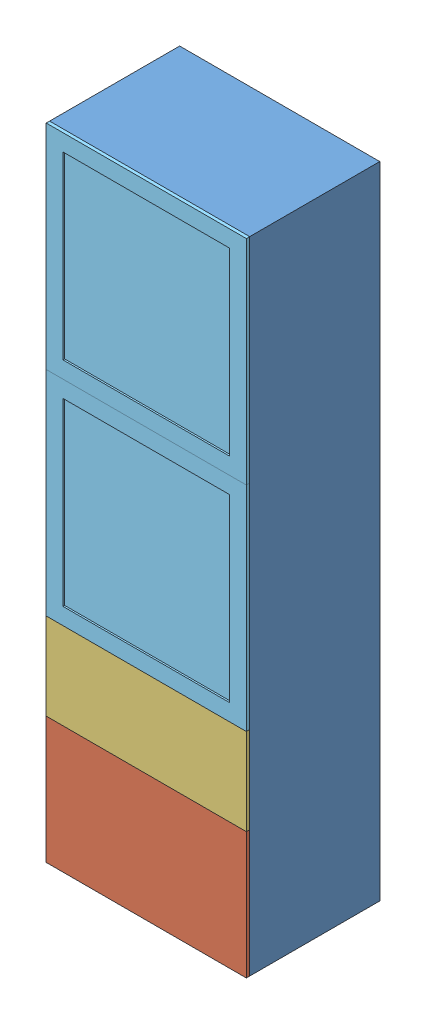
SolidWorks assembly Schrank-L, configuration Standard. Lengths in mm.
Overall size (600 1920 400).
10 component instances, 5 part files, 23 mates.
Components (placement in the parent):
- Schrank-Korpus-1: Schrank-Korpus [Standard] at (-405.9631 38.7369 1725) size (600 1920 390)
- Schublade-Hoch-1: Schublade-Hoch [Standard] at (-405.9631 -731.2631 2115) size (600 380 380)
- Schublade-Tief-1: Schublade-Tief [Standard] at (-405.9631 -411.2631 2115) size (600 260 380)
- Regalbrett-1: Regalbrett [Standard] at (-405.9631 -286.2631 1735) x (1 0 0) z (0 -1 0) size (560 360 10)
- Regalbrett-2: Regalbrett [Standard] at (-405.9631 -20.5713 1735) x (1 0 0) z (0 -1 0) size (560 360 10)
- Regalbrett-3: Regalbrett [Standard] at (-405.9631 223.3159 1735) x (1 0 0) z (0 -1 0) size (560 360 10)
- Regalbrett-4: Regalbrett [Standard] at (-405.9631 479.3348 1735) x (1 0 0) z (0 -1 0) size (560 360 10)
- Regalbrett-5: Regalbrett [Standard] at (-405.9631 753.23 1735) x (1 0 0) z (0 -1 0) size (560 360 10)
- SINDVIK-Vitrinentüre-1: SINDVIK-Vitrinentüre [Standard] at (-405.9631 38.7369 2115) size (600 640 10)
- SINDVIK-Vitrinentüre-2: SINDVIK-Vitrinentüre [Standard] at (-405.9631 678.7369 2115) size (600 640 10)
Mates (geometry in assembly coordinates):
- Deckungsgleich1: coincident anti-aligned: plane of Schrank-Korpus-1 through (-125.9631 978.7369 2115) normal (-1 0 0); plane of Schublade-Hoch-1 through (-125.9631 -901.2631 1755) normal (1 0 0)
- Deckungsgleich2: coincident anti-aligned: plane of Schrank-Korpus-1 through (-125.9631 978.7369 2115) normal (-1 0 0); plane of Schublade-Tief-1 through (-125.9631 -321.2631 1755) normal (1 0 0)
- Deckungsgleich3: coincident anti-aligned: plane of Schrank-Korpus-1 through (-405.9631 38.7369 1735) normal (0 0 1); plane of Regalbrett-1 through (-405.9631 -286.2631 1735) normal (0 0 -1)
- Deckungsgleich4: coincident aligned: plane of Schublade-Tief-1 through (-705.9631 -281.2631 2125) normal (0 1 0); plane of Regalbrett-1 through (-685.9631 -281.2631 2095) normal (0 1 0)
- Deckungsgleich5: coincident: plane of Schrank-Korpus-1 through (-405.9631 38.7369 1735) normal (0 0 1); plane of Regalbrett-2 through (-405.9631 -20.5713 1735) normal (0 0 -1)
- Deckungsgleich6: coincident: plane of Schrank-Korpus-1 through (-405.9631 38.7369 1735) normal (0 0 1); plane of Regalbrett-3 through (-405.9631 223.3159 1735) normal (0 0 -1)
- Deckungsgleich7: coincident: plane of Schrank-Korpus-1 through (-405.9631 38.7369 1735) normal (0 0 1); plane of Regalbrett-4 through (-405.9631 479.3348 1735) normal (0 0 -1)
- Deckungsgleich8: coincident: plane of Schrank-Korpus-1 through (-405.9631 38.7369 1735) normal (0 0 1); plane of Regalbrett-5 through (-405.9631 753.23 1735) normal (0 0 -1)
- Deckungsgleich9: coincident anti-aligned: plane of Schrank-Korpus-1 through (-685.9631 978.7369 2115) normal (1 0 0); plane of Regalbrett-5 through (-685.9631 748.23 2095) normal (-1 0 0)
- Deckungsgleich10: coincident anti-aligned: plane of Schrank-Korpus-1 through (-685.9631 978.7369 2115) normal (1 0 0); plane of Regalbrett-4 through (-685.9631 474.3348 2095) normal (-1 0 0)
- Deckungsgleich11: coincident anti-aligned: plane of Schrank-Korpus-1 through (-685.9631 978.7369 2115) normal (1 0 0); plane of Regalbrett-3 through (-685.9631 218.3159 2095) normal (-1 0 0)
- Deckungsgleich12: coincident anti-aligned: plane of Schrank-Korpus-1 through (-685.9631 978.7369 2115) normal (1 0 0); plane of Regalbrett-2 through (-685.9631 -25.5713 2095) normal (-1 0 0)
- Deckungsgleich13: coincident anti-aligned: plane of Schrank-Korpus-1 through (-685.9631 978.7369 2115) normal (1 0 0); plane of Regalbrett-1 through (-685.9631 -291.2631 2095) normal (-1 0 0)
- Deckungsgleich14: coincident anti-aligned: plane of Schrank-Korpus-1 through (-685.9631 -901.2631 2115) normal (0 1 0); plane of Schublade-Hoch-1 through (-685.9631 -901.2631 1755) normal (0 -1 0)
- Deckungsgleich15: coincident: line of Schublade-Hoch-1 through (-105.9631 -541.2631 2115) axis (-1 0 0); plane of Schublade-Tief-1 through (-705.9631 -541.2631 2125) normal (0 -1 0)
- Deckungsgleich16: coincident anti-aligned: plane of Schrank-Korpus-1 through (-405.9631 38.7369 2115) normal (0 0 1); plane of Schublade-Hoch-1 through (-405.9631 -731.2631 2115) normal (0 0 -1)
- Deckungsgleich17: coincident anti-aligned: plane of Schrank-Korpus-1 through (-405.9631 38.7369 2115) normal (0 0 1); plane of Schublade-Tief-1 through (-405.9631 -411.2631 2115) normal (0 0 -1)
- Deckungsgleich18: coincident anti-aligned: plane of Schrank-Korpus-1 through (-405.9631 38.7369 2115) normal (0 0 1); plane of SINDVIK-Vitrinentüre-1 through (-405.9631 38.7369 2115) normal (0 0 -1)
- Deckungsgleich19: coincident: plane of Schrank-Korpus-1 through (-405.9631 38.7369 2115) normal (0 0 1); plane of SINDVIK-Vitrinentüre-2 through (-405.9631 678.7369 2115) normal (0 0 -1)
- Deckungsgleich20: coincident anti-aligned: plane of Schublade-Tief-1 through (-705.9631 -281.2631 2125) normal (0 1 0); plane of SINDVIK-Vitrinentüre-1 through (-705.9631 -281.2631 2125) normal (0 -1 0)
- Deckungsgleich21: coincident: plane of SINDVIK-Vitrinentüre-1 through (-705.9631 358.7369 2125) normal (0 1 0); plane of SINDVIK-Vitrinentüre-2 through (-705.9631 358.7369 2125) normal (0 -1 0)
- Deckungsgleich22: coincident aligned: plane of Schrank-Korpus-1 through (-705.9631 -921.2631 1735) normal (-1 0 0); plane of SINDVIK-Vitrinentüre-1 through (-705.9631 -281.2631 2125) normal (-1 0 0)
- Deckungsgleich23: coincident aligned: plane of Schrank-Korpus-1 through (-705.9631 -921.2631 1735) normal (-1 0 0); plane of SINDVIK-Vitrinentüre-2 through (-705.9631 358.7369 2125) normal (-1 0 0)
